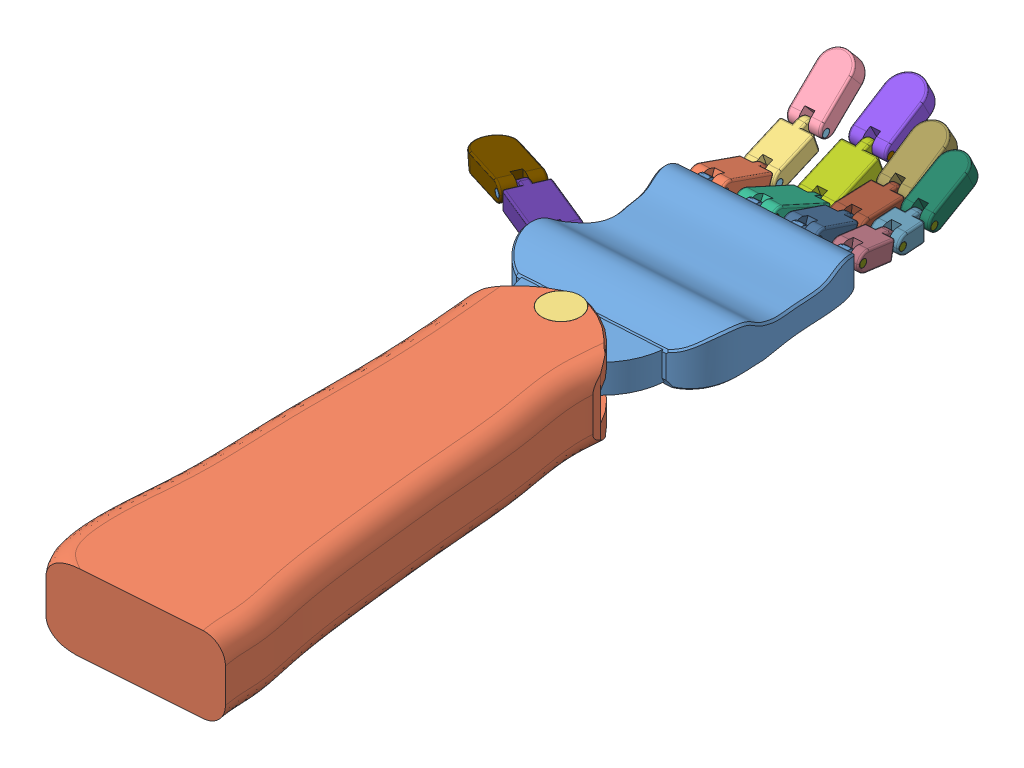
SolidWorks assembly Hand, configuration Default. Lengths in mm.
Overall size (2132.29 632.71 4620.92).
31 component instances, 21 part files, 60 mates.
Components (placement in the parent):
- palm-1: palm [Default] at (-41.8417 0 -1.1985) x (0.998166 0 -0.060532) z (0.060532 0 0.998166) size (1069.09 253.19 1333.97)
- bottomIndex-1: bottomIndex [Default] at (-437.3162 88.2883 -603.9878) x (0.998166 0 -0.060532) z (-0.021936 0.932025 -0.361729) size (172.17 374 100.1)
- upIndex-1: upIndex [Default] at (-452.4944 48.7205 -850.9701) x (0.998166 0 -0.060532) z (0.019738 0.945344 0.325476) size (172.17 324 100.1)
- topIndex-1: topIndex [Default] at (-466.3955 161.7655 -1076.8941) x (0.998166 0 -0.060532) z (0.039268 0.761029 0.647529) size (172.17 335 100.1)
- WhitepinIndex_Ring-1: WhitepinIndex_Ring [Default] at (-378.9081 58.8423 -1038.4525) x (-0.058411 0.26237 -0.963198) z (-0.998166 0 0.060532) size (40 40 170)
- WhitepinIndex_Ring-2: WhitepinIndex_Ring [Default] at (-362.9148 -31.1541 -778.028) x (0.060532 0.002871 0.998162) z (-0.998166 0 0.060532) size (40 40 170)
- WhitepinIndex_Ring-3: WhitepinIndex_Ring [Default] at (-344.3231 86.9862 -474.7571) x (0.060532 0 0.998166) z (-0.998166 0 0.060532) size (40 40 170)
- bottomMiddle-1: bottomMiddle [Default] at (-199.0941 66.0714 -640.5767) x (0.998166 0 -0.060532) z (-0.02657 0.898518 -0.438133) size (192.17 424 100.1)
- upMiddle-1: upMiddle [Default] at (-215.9819 10.7713 -922.3574) x (0.998166 0 -0.060532) z (0.020188 0.942748 0.332895) size (192.17 374 100.1)
- topmiddle-2: topmiddle [Default] at (-232.605 121.5272 -1193.167) x (0.998166 0 -0.060532) z (0.028224 0.884647 0.465407) size (192.17 345 100.1)
- Whitepinmiddle-1: Whitepinmiddle [Default] at (-323.487 30.6687 -1122.3843) x (0.004965 -0.99663 0.08188) z (0.998166 0 -0.060532) size (40 40 190)
- Whitepinmiddle-2: Whitepinmiddle [Default] at (-115.0322 -78.0543 -827.1253) x (0.060532 -0.000312 0.998166) z (-0.998166 0 0.060532) size (40 40 190)
- bottomRing-1: bottomRing [Default] at (26.9003 98.3286 -608.7002) x (0.998166 0 -0.060532) z (-0.021438 0.935182 -0.353517) size (172.17 324 100.1)
- Whitepinmiddle-3: Whitepinmiddle [Default] at (-94.7815 86.9862 -489.8901) x (-0.007661 0.991958 -0.126334) z (-0.998166 0 0.060532) size (40 40 190)
- upRing-1: upRing [Default] at (12.0861 36.8726 -856.2884) x (0.998166 0 -0.060532) z (-0.001422 0.999724 -0.023454) size (172.17 324 100.1)
- topring-1: topring [Default] at (-2.0523 75.729 -1092.732) x (0.998166 0 -0.060532) z (0.029992 0.868627 0.494559) size (172.17 335 100.1)
- WhitepinIndex_Ring-4: WhitepinIndex_Ring [Default] at (86.5503 -17.2491 -1035.9018) x (0.060532 -0.000198 0.998166) z (-0.998166 0 0.060532) size (40 40 170)
- WhitepinIndex_Ring-5: WhitepinIndex_Ring [Default] at (103.0529 -10.7638 -760.4719) x (0.060532 0.000705 0.998166) z (-0.998166 0 0.060532) size (40 40 170)
- WhitepinIndex_Ring-6: WhitepinIndex_Ring [Default] at (118.4772 86.9862 -502.8228) x (0.060532 0 0.998166) z (-0.998166 0 0.060532) size (40 40 170)
- bottomlittle-1: bottomlittle [Default] at (258.1944 122.4264 -594.3273) x (0.998166 0 -0.060532) z (-0.01107 0.983134 -0.182551) size (152.17 274 100.1)
- uplittle-1: uplittle [Default] at (246.9614 96.0897 -782.8624) x (0.998166 0 -0.060532) z (0.00053 0.999962 0.008738) size (152.17 224 100.1)
- toplittle-1: toplittle [Default] at (235.3833 135.836 -977.0881) x (0.998166 0 -0.060532) z (0.026427 0.899665 0.43578) size (152.17 325 100.1)
- Whitepinlittle-1: Whitepinlittle [Default] at (175.0989 45.6539 -728.853) x (-0.060532 0 -0.998166) z (0.998166 0 -0.060532) size (40 40 150)
- Whitepinlittle-2: Whitepinlittle [Default] at (188.3488 86.9862 -507.06) x (-0.060532 0 -0.998166) z (0.998166 0 -0.060532) size (40 40 150)
- Whitepinlittle-3: Whitepinlittle [Default] at (164.6453 47.1947 -904.5356) x (-0.060532 0 -0.998166) z (0.998166 0 -0.060532) size (40 40 150)
- bottomthumb-1: bottomthumb [Default] at (-709.0963 131.3541 109.3699) x (0.397176 0 -0.917743) z (-0.034246 0.999304 -0.014821) size (202.17 424 100.1)
- topThumb-1: topThumb [Default] at (-1035.2131 102.0106 -31.9832) x (0.397176 0 -0.917743) z (-0.148912 0.986748 -0.064445) size (202.17 400 100.1)
- Whitepinthumb-1: Whitepinthumb [Default] at (-874.8523 72.9556 -71.5461) x (0.917743 0 0.397176) z (-0.397176 0 0.917743) size (40 40 200)
- Whitepinthumb-2: Whitepinthumb [Default] at (-530.1009 86.9862 77.8715) x (0.917743 0 0.397176) z (-0.397176 0 0.917743) size (40 40 200)
- arm-1: arm [Default] at (-27.8969 106.1035 869.5439) x (0.997466 0 -0.071141) z (0.071141 0 0.997466) size (1268.57 632.71 2564.87)
- armpin-1: armpin [Default] at (-40.7023 -93.8965 690) x (1 0 0) z (0 1 0) size (200 200 400)
Mates (geometry in assembly coordinates):
- Concentric1: concentric: cylinder of assembly; cylinder of assembly; cylinder of palm-1 through (-656.4121 86.9862 -455.831) axis (0.998166 0 -0.060532) radius 20; cylinder of bottomIndex-1 through (-344.3231 86.9862 -474.7571) axis (-0.998166 0 0.060532) radius 20
- Coincident1: coincident: plane of assembly; plane of assembly; plane of palm-1 through (-405.6053 136.9862 -494.083) normal (0.998166 0 -0.060532); plane of bottomIndex-1 through (-400.2953 58.5046 -406.5229) normal (-0.998166 0 0.060532)
- Concentric2: concentric: cylinder of assembly; cylinder of assembly; cylinder of bottomIndex-1 through (-533.4878 -31.1541 -767.6839) axis (0.998166 0 -0.060532) radius 20; cylinder of upIndex-1 through (-362.9148 -31.1541 -778.028) axis (-0.998166 0 0.060532) radius 20
- Coincident2: coincident: plane of assembly; plane of assembly; plane of bottomIndex-1 through (-418.8306 -59.2733 -708.8635) normal (0.998166 0 -0.060532); plane of upIndex-1 through (-420.9304 -94.725 -743.4893) normal (-0.998166 0 0.060532)
- Concentric3: concentric: cylinder of assembly; cylinder of assembly; cylinder of upIndex-1 through (-549.4812 58.8423 -1028.1084) axis (0.998166 0 -0.060532) radius 20; cylinder of topIndex-1 through (-378.9081 58.8423 -1038.4525) axis (-0.998166 0 0.060532) radius 20
- Coincident3: coincident: plane of upIndex-1 through (-436.8666 -5.0547 -1002.9702) normal (0.998166 0 -0.060532); plane of topIndex-1 through (-438.4582 -11.6451 -1029.2154) normal (-0.998166 0 0.060532)
- Concentric4: concentric: cylinder of topIndex-1 through (-378.9081 58.8423 -1038.4525) axis (-0.998166 0 0.060532) radius 20; cylinder of WhitepinIndex_Ring-1 through (-548.5964 58.8423 -1028.1621) axis (0.998166 0 -0.060532) radius 20
- Coincident4: coincident: plane of topIndex-1 through (-560.9248 166.7525 -1231.4559) normal (-0.998166 0 0.060532); plane of WhitepinIndex_Ring-1 through (-548.5964 58.8423 -1028.1621) normal (-0.998166 0 0.060532)
- Concentric5: concentric: cylinder of assembly; cylinder of assembly; cylinder of upIndex-1 through (-362.9148 -31.1541 -778.028) axis (-0.998166 0 0.060532) radius 20; cylinder of WhitepinIndex_Ring-2 through (-532.603 -31.1541 -767.7376) axis (0.998166 0 -0.060532) radius 20
- Coincident5: coincident: plane of upIndex-1 through (-376.777 -5.0547 -1006.6143) normal (0.998166 0 -0.060532); plane of WhitepinIndex_Ring-2 through (-362.9148 -31.1541 -778.028) normal (0.998166 0 -0.060532)
- Concentric6: concentric: cylinder of assembly; cylinder of assembly; cylinder of bottomIndex-1 through (-344.3231 86.9862 -474.7571) axis (-0.998166 0 0.060532) radius 20; cylinder of WhitepinIndex_Ring-3 through (-514.0113 86.9862 -464.4666) axis (0.998166 0 -0.060532) radius 20
- Coincident6: coincident: plane of bottomIndex-1 through (-358.741 -59.2733 -712.5076) normal (0.998166 0 -0.060532); plane of WhitepinIndex_Ring-3 through (-344.3231 86.9862 -474.7571) normal (0.998166 0 -0.060532)
- Concentric7: concentric: cylinder of assembly; cylinder of assembly; cylinder of palm-1 through (-656.4121 86.9862 -455.831) axis (0.998166 0 -0.060532) radius 20; cylinder of bottomMiddle-1 through (-94.7815 86.9862 -489.8901) axis (-0.998166 0 0.060532) radius 20
- Coincident7: coincident: plane of palm-1 through (-166.0454 136.9862 -508.6107) normal (0.998166 0 -0.060532); plane of bottomMiddle-1 through (-160.6052 64.0072 -418.9027) normal (-0.998166 0 0.060532)
- Concentric8: concentric: cylinder of bottomMiddle-1 through (-305.9678 -78.0543 -815.5463) axis (0.998166 0 -0.060532) radius 20; cylinder of upMiddle-1 through (-115.0322 -78.0543 -827.1253) axis (-0.998166 0 0.060532) radius 20
- Coincident8: coincident: plane of bottomMiddle-1 through (-230.7098 -100.5944 -752.2144) normal (-0.998166 0 0.060532); plane of upMiddle-1 through (-232.9682 -141.867 -789.4552) normal (0.998166 0 -0.060532)
- Concentric9: concentric: cylinder of upMiddle-1 through (-324.3718 30.6687 -1122.3307) axis (0.998166 0 -0.060532) radius 20; cylinder of topmiddle-2 through (-133.8355 30.6687 -1133.8854) axis (-0.998166 0 0.060532) radius 20
- Coincident9: coincident: plane of upMiddle-1 through (-201.8061 -33.4775 -1098.3009) normal (0.998166 0 -0.060532); plane of topmiddle-2 through (-202.4408 -36.8768 -1108.7673) normal (-0.998166 0 0.060532)
- Concentric10: concentric: cylinder of upMiddle-1 through (-324.3718 30.6687 -1122.3307) axis (0.998166 0 -0.060532) radius 20; cylinder of Whitepinmiddle-1 through (-133.8355 30.6687 -1133.8854) axis (-0.998166 0 0.060532) radius 20
- Coincident10: coincident: plane of topmiddle-2 through (-336.9469 91.3452 -1344.3352) normal (-0.998166 0 0.060532); plane of Whitepinmiddle-1 through (-323.487 30.6687 -1122.3843) normal (-0.998166 0 0.060532)
- Concentric11: concentric: cylinder of upMiddle-1 through (-115.0322 -78.0543 -827.1253) axis (-0.998166 0 0.060532) radius 20; cylinder of Whitepinmiddle-2 through (-304.6837 -78.0543 -815.6242) axis (0.998166 0 -0.060532) radius 20
- Coincident11: coincident: plane of upMiddle-1 through (-321.3864 -33.4775 -1091.0492) normal (-0.998166 0 0.060532); plane of Whitepinmiddle-2 through (-304.6837 -78.0543 -815.6242) normal (-0.998166 0 0.060532)
- Concentric12: concentric: cylinder of assembly; cylinder of assembly; cylinder of palm-1 through (-656.4121 86.9862 -455.831) axis (0.998166 0 -0.060532) radius 20; cylinder of bottomRing-1 through (118.4772 86.9862 -502.8228) axis (-0.998166 0 0.060532) radius 20
- Coincident12: coincident: plane of palm-1 through (57.195 136.9862 -522.1487) normal (0.998166 0 -0.060532); plane of bottomRing-1 through (62.4895 57.9354 -434.8416) normal (-0.998166 0 0.060532)
- Concentric13: concentric: cylinder of bottomMiddle-1 through (-94.7815 86.9862 -489.8901) axis (-0.998166 0 0.060532) radius 20; cylinder of Whitepinmiddle-3 through (-284.4331 86.9862 -478.389) axis (0.998166 0 -0.060532) radius 20
- Coincident13: coincident: plane of bottomMiddle-1 through (-111.1295 -100.5944 -759.4662) normal (0.998166 0 -0.060532); plane of Whitepinmiddle-3 through (-94.7815 86.9862 -489.8901) normal (0.998166 0 -0.060532)
- Concentric14: concentric: cylinder of bottomRing-1 through (-67.9195 -10.7638 -750.1036) axis (0.998166 0 -0.060532) radius 20; cylinder of upRing-1 through (103.0529 -10.7638 -760.4719) axis (-0.998166 0 0.060532) radius 20
- Coincident14: coincident: plane of bottomRing-1 through (-2.7865 -39.4604 -688.5307) normal (-0.998166 0 0.060532); plane of upRing-1 through (-3.6485 -59.5752 -702.7461) normal (0.998166 0 -0.060532)
- Concentric15: concentric: cylinder of upRing-1 through (-84.4221 -17.2491 -1025.5335) axis (0.998166 0 -0.060532) radius 20; cylinder of topring-1 through (86.5503 -17.2491 -1035.9018) axis (-0.998166 0 0.060532) radius 20
- Coincident15: coincident: plane of upRing-1 through (-20.0906 -66.0369 -977.1782) normal (-0.998166 0 0.060532); plane of topring-1 through (-22.1186 -85.4538 -1010.6195) normal (0.998166 0 -0.060532)
- Concentric16: concentric: cylinder of topring-1 through (86.5503 -17.2491 -1035.9018) axis (-0.998166 0 0.060532) radius 20; cylinder of WhitepinIndex_Ring-4 through (-83.138 -17.2491 -1025.6114) axis (0.998166 0 -0.060532) radius 20
- Coincident16: coincident: plane of topring-1 through (73.2202 50.7998 -1255.7123) normal (0.998166 0 -0.060532); plane of WhitepinIndex_Ring-4 through (86.5503 -17.2491 -1035.9018) normal (0.998166 0 -0.060532)
- Concentric19: concentric: cylinder of upRing-1 through (103.0529 -10.7638 -760.4719) axis (-0.998166 0 0.060532) radius 20; cylinder of WhitepinIndex_Ring-5 through (-66.6354 -10.7638 -750.1814) axis (0.998166 0 -0.060532) radius 20
- Concentric20: concentric: cylinder of bottomRing-1 through (118.4772 86.9862 -502.8228) axis (-0.998166 0 0.060532) radius 20; cylinder of WhitepinIndex_Ring-6 through (-51.2111 86.9862 -492.5323) axis (0.998166 0 -0.060532) radius 20
- Coincident21: coincident: plane of upRing-1 through (89.508 -66.0369 -983.8246) normal (0.998166 0 -0.060532); plane of WhitepinIndex_Ring-5 through (103.0529 -10.7638 -760.4719) normal (0.998166 0 -0.060532)
- Coincident22: coincident: plane of bottomRing-1 through (106.8122 -39.4604 -695.1771) normal (0.998166 0 -0.060532); plane of WhitepinIndex_Ring-6 through (118.4772 86.9862 -502.8228) normal (0.998166 0 -0.060532)
- Concentric21: concentric: cylinder of assembly; cylinder of assembly; cylinder of palm-1 through (-656.4121 86.9862 -455.831) axis (0.998166 0 -0.060532) radius 20; cylinder of bottomlittle-1 through (338.0737 86.9862 -516.1398) axis (-0.998166 0 0.060532) radius 20
- Coincident23: coincident: plane of palm-1 through (286.7732 136.9862 -536.0711) normal (0.998166 0 -0.060532); plane of bottomlittle-1 through (291.6945 46.9738 -454.9191) normal (-0.998166 0 0.060532)
- Concentric22: concentric: cylinder of bottomlittle-1 through (173.8149 45.6539 -728.7751) axis (0.998166 0 -0.060532) radius 20; cylinder of uplittle-1 through (324.8239 45.6539 -737.9328) axis (-0.998166 0 0.060532) radius 20
- Coincident24: coincident: plane of bottomlittle-1 through (228.5958 5.8244 -672.7042) normal (-0.998166 0 0.060532); plane of uplittle-1 through (228.0072 -4.7819 -682.4101) normal (0.998166 0 -0.060532)
- Concentric23: concentric: cylinder of uplittle-1 through (163.3613 47.1947 -904.4578) axis (0.998166 0 -0.060532) radius 20; cylinder of toplittle-1 through (314.3703 47.1947 -913.6154) axis (-0.998166 0 0.060532) radius 20
- Coincident25: coincident: plane of uplittle-1 through (217.6142 -3.2499 -857.0946) normal (-0.998166 0 0.060532); plane of toplittle-1 through (215.9552 -19.6176 -884.4505) normal (0.998166 0 -0.060532)
- Concentric24: concentric: cylinder of assembly; cylinder of assembly; cylinder of palm-1 through (-656.4121 86.9862 -455.831) axis (0.998166 0 -0.060532) radius 20; cylinder of Whitepinlittle-2 through (338.0737 86.9862 -516.1398) axis (-0.998166 0 0.060532) radius 20
- Coincident26: coincident: plane of bottomlittle-1 through (328.2128 5.8244 -678.7453) normal (0.998166 0 -0.060532); plane of Whitepinlittle-2 through (338.0737 86.9862 -516.1398) normal (0.998166 0 -0.060532)
- Concentric25: concentric: cylinder of bottomlittle-1 through (173.8149 45.6539 -728.7751) axis (0.998166 0 -0.060532) radius 20; cylinder of Whitepinlittle-1 through (324.8239 45.6539 -737.9328) axis (-0.998166 0 0.060532) radius 20
- Coincident27: coincident: plane of uplittle-1 through (317.2312 -3.2499 -863.1357) normal (0.998166 0 -0.060532); plane of Whitepinlittle-1 through (324.8239 45.6539 -737.9328) normal (0.998166 0 -0.060532)
- Concentric26: concentric: cylinder of uplittle-1 through (163.3613 47.1947 -904.4578) axis (0.998166 0 -0.060532) radius 20; cylinder of Whitepinlittle-3 through (314.3703 47.1947 -913.6154) axis (-0.998166 0 0.060532) radius 20
- Coincident28: coincident: plane of toplittle-1 through (300.7957 100.442 -1137.4579) normal (0.998166 0 -0.060532); plane of Whitepinlittle-3 through (314.3703 47.1947 -913.6154) normal (0.998166 0 -0.060532)
- Concentric27: concentric: cylinder of assembly; cylinder of assembly; cylinder of palm-1 through (-550.3568 86.9862 124.6764) axis (-0.397176 0 0.917743) radius 20; cylinder of bottomthumb-1 through (-530.1009 86.9862 77.8715) axis (-0.397176 0 0.917743) radius 20
- Coincident29: coincident: plane of palm-1 through (-600.8559 136.9862 183.4543) normal (-0.397176 0 0.917743); plane of bottomthumb-1 through (-532.1804 38.8868 213.1754) normal (0.397176 0 -0.917743)
- Concentric28: concentric: cylinder of bottomthumb-1 through (-954.7984 72.9556 113.183) axis (0.397176 0 -0.917743) radius 20; cylinder of topThumb-1 through (-874.8523 72.9556 -71.5461) axis (-0.397176 0 0.917743) radius 20
- Coincident30: coincident: plane of bottomthumb-1 through (-876.0147 24.8935 64.1546) normal (-0.397176 0 0.917743); plane of topThumb-1 through (-871.7746 31.7312 65.9896) normal (0.397176 0 -0.917743)
- Concentric29: concentric: cylinder of topThumb-1 through (-874.8523 72.9556 -71.5461) axis (-0.397176 0 0.917743) radius 20; cylinder of Whitepinthumb-1 through (-954.2875 72.9556 112.0024) axis (0.397176 0 -0.917743) radius 20
- Coincident31: coincident: plane of topThumb-1 through (-1195.8766 -21.0031 7.4487) normal (-0.397176 0 0.917743); plane of Whitepinthumb-1 through (-954.2875 72.9556 112.0024) normal (-0.397176 0 0.917743)
- Concentric30: concentric: cylinder of bottomthumb-1 through (-530.1009 86.9862 77.8715) axis (-0.397176 0 0.917743) radius 20; cylinder of Whitepinthumb-2 through (-609.5361 86.9862 261.42) axis (0.397176 0 -0.917743) radius 20
- Coincident32: coincident: plane of bottomthumb-1 through (-905.8823 24.8935 133.1688) normal (-0.397176 0 0.917743); plane of Whitepinthumb-2 through (-609.5361 86.9862 261.42) normal (-0.397176 0 0.917743)
- Concentric31: concentric: cylinder of assembly; cylinder of assembly; cylinder of palm-1 through (-40.7023 -8.0165 690) axis (0 1 0) radius 100; cylinder of arm-1 through (-40.7023 -93.8965 690) axis (0 1 0) radius 100
- Coincident33: coincident: plane of palm-1 through (-382.1913 181.6035 840.9478) normal (0 1 0); plane of arm-1 through (-377.0101 181.6035 894.4433) normal (0 -1 0)
- Concentric32: concentric: cylinder of assembly; cylinder of assembly; cylinder of palm-1 through (-40.7023 -8.0165 690) axis (0 1 0) radius 100; cylinder of armpin-1 through (-40.7023 306.1035 690) axis (0 -1 0) radius 100
- Coincident34: coincident: plane of arm-1 through (-27.8969 306.1035 869.5439) normal (0 1 0); plane of armpin-1 through (-40.7023 306.1035 690) normal (0 1 0)
